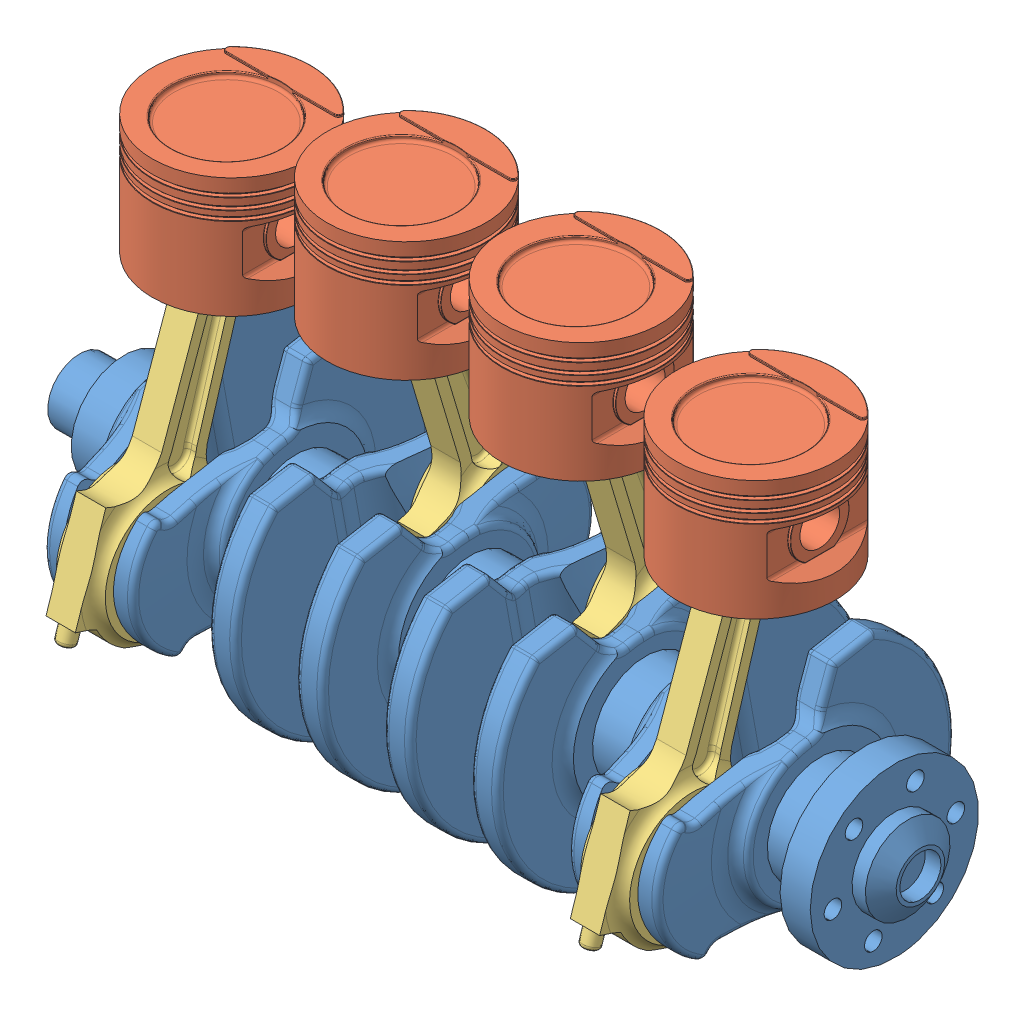
SolidWorks assembly Engine4c, configuration Default. Lengths in mm.
Overall size (462.5 284.87 180.95).
13 component instances, 3 part files, 10 mates.
Components (placement in the parent):
- Crankshaft-1: Crankshaft [Default] at (-1.3622 0 0) x (1 0 0) z (0 0.983907 0.178684) size (429.6 147.6 117)
- piston_rod-1: piston_rod [Default] at (29.6993 129.7644 0) size (81 215.54 130.97) (flexible)
  - Piston-1: Piston [Default] at (1.4385 31.8218 0) size (81 62.3 81)
  - ConRod-1: ConRod [Default] at (12.4385 -0.1282 0) x (0 0.310779 0.950482) z (-1 0 0) size (72.5 196.5 26.37)
- piston_rod-2: piston_rod [Default] at (118.9993 146.1318 0) size (81 215.54 130.97) (flexible)
  - Piston-1: Piston [Default] at (1.4385 31.8218 0) size (81 62.3 81)
  - ConRod-1: ConRod [Default] at (12.4385 -0.1282 0) x (0 -0.310779 0.950482) z (-1 0 0) size (72.5 196.5 26.37)
- piston_rod-3: piston_rod [Default] at (208.2993 146.1318 0) size (81 215.54 130.97) (flexible)
  - Piston-1: Piston [Default] at (1.4385 31.8218 0) size (81 62.3 81)
  - ConRod-1: ConRod [Default] at (12.4385 -0.1282 0) x (0 -0.310779 0.950482) z (-1 0 0) size (72.5 196.5 26.37)
- piston_rod-4: piston_rod [Default] at (297.5993 129.7644 0) size (81 215.54 130.97) (flexible)
  - Piston-1: Piston [Default] at (1.4385 31.8218 0) size (81 62.3 81)
  - ConRod-1: ConRod [Default] at (12.4385 -0.1282 0) x (0 0.310779 0.950482) z (-1 0 0) size (72.5 196.5 26.37)
Mates (geometry in assembly coordinates):
- Concentrico1: concentric aligned: cylinder of Crankshaft-1 through (-46.5622 0 0) axis (1 0 0) radius 16.3; line of assembly
- Concentrico2: concentric aligned: cylinder of Crankshaft-1 through (111.8201 -8.1837 45.0629) axis (-1 0 0) radius 24; cylinder of piston_rod-1/ConRod-1 through (41.6378 -8.1837 45.0629) axis (-1 0 0) radius 24
- Coincidente2: coincident anti-aligned: plane of Crankshaft-1 through (18.6378 0 0) normal (1 0 0); plane of piston_rod-1/ConRod-1 through (18.6378 -8.1837 45.0629) normal (-1 0 0)
- Concentrico3: concentric aligned: cylinder of piston_rod-1/Piston-1 through (31.1378 100.2862 0) axis (0 1 0) radius 40.5; line of assembly
- Concentrico4: concentric anti-aligned: cylinder of piston_rod-2/ConRod-1 through (130.9378 8.1837 -45.0629) axis (-1 0 0) radius 24; cylinder of Crankshaft-1 through (40.0556 8.1837 -45.0629) axis (1 0 0) radius 24
- Concentrico5: concentric anti-aligned: cylinder of piston_rod-2/Piston-1 through (120.4378 116.6537 0) axis (0 1 0) radius 40.5
- Concentrico6: concentric aligned: cylinder of Crankshaft-1 through (290.4201 8.1837 -45.0629) axis (-1 0 0) radius 24; cylinder of piston_rod-3/ConRod-1 through (220.2378 8.1837 -45.0629) axis (-1 0 0) radius 24
- Concentrico7: concentric anti-aligned: cylinder of piston_rod-3/Piston-1 through (209.7378 116.6537 0) axis (0 1 0) radius 40.5
- Concentrico8: concentric anti-aligned: cylinder of Crankshaft-1 through (218.6556 -8.1837 45.0629) axis (1 0 0) radius 24; cylinder of piston_rod-4/ConRod-1 through (309.5378 -8.1837 45.0629) axis (-1 0 0) radius 24
- Concentrico9: concentric anti-aligned: cylinder of piston_rod-4/Piston-1 through (299.0378 100.2862 0) axis (0 1 0) radius 40.5
